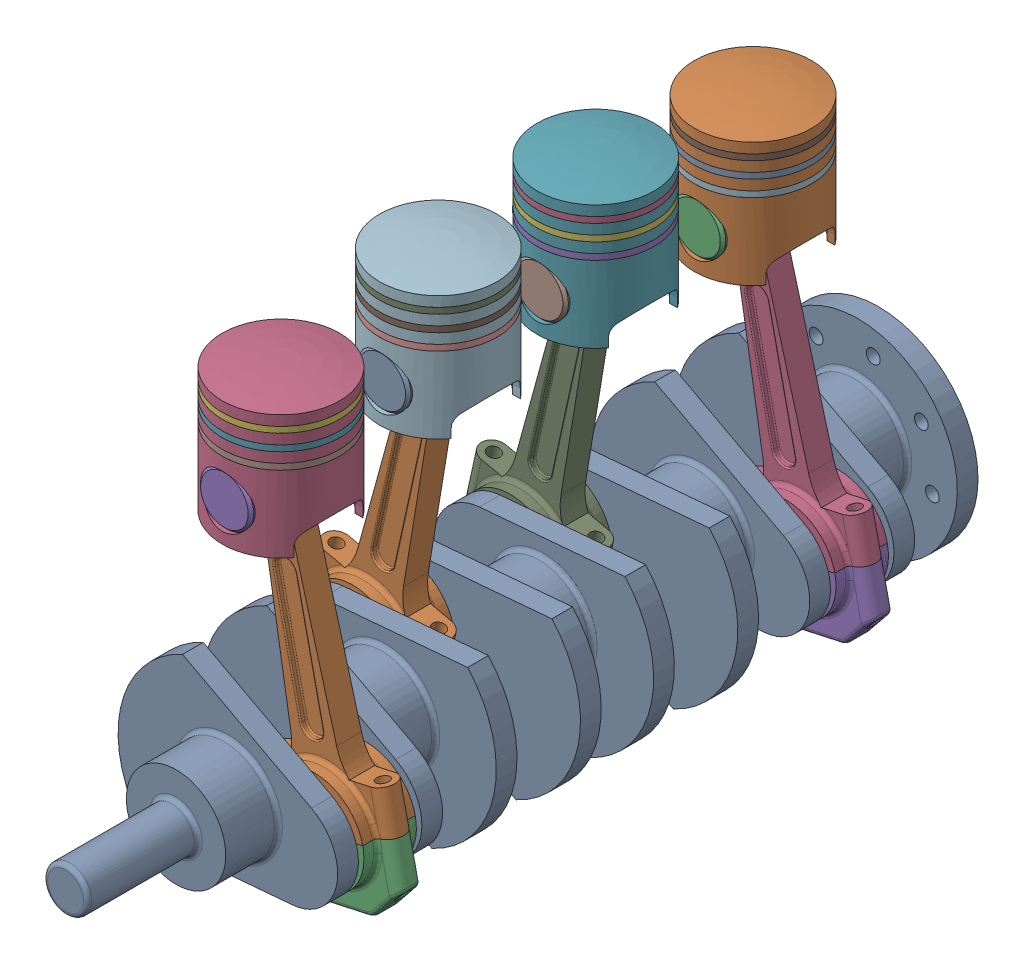
SolidWorks assembly Four cylinder engine, configuration Default. Lengths in mm.
Overall size (199.45 359.98 589).
29 component instances, 6 part files, 66 mates.
Components (placement in the parent):
- Crankshafts-1: Crankshafts [Default] at (0 0 456) x (0.200957 0.9796 0) z (0 0 1) size (144 160 589)
- Connecting rod-1: Connecting rod [Default] at (0 187.6868 433) x (0.976784 0.214227 0) z (0 0 1) size (94 223.7 38)
- Connecting Rod Cap-1: Connecting Rod Cap [Default] at (43.1024 -8.8421 433) x (0.976784 0.214227 0) z (0 0 -1) size (94 50 38)
- Piston-1: Piston [Default] at (0 160.6868 433) size (85 95 85)
- Piston Pin-1: Piston Pin [Default] at (0 187.6868 433) x (1 -0.000021 0) z (0 0 1) size (38.5 38.5 82)
- Piston Ring-1: Piston Ring [Default] at (0 239.0868 433) size (85 4.3 85)
- Piston Ring-2: Piston Ring [Default] at (0 227.4868 433) x (0.982082 0 -0.188455) z (0.188455 0 0.982082) size (85 4.3 85)
- Piston Ring-3: Piston Ring [Default] at (0 215.8868 433) x (0.918365 0 -0.395734) z (0.395734 0 0.918365) size (85 4.3 85)
- Piston Ring-4: Piston Ring [Default] at (0 256.771 319) x (0.941458 0 -0.337131) z (0.337131 0 0.941458) size (85 4.3 85)
- Piston Ring-5: Piston Ring [Default] at (0 233.571 319) x (0.731188 0 -0.682176) z (0.682176 0 0.731188) size (85 4.3 85)
- Piston Ring-6: Piston Ring [Default] at (0 245.171 319) x (0.861055 0 -0.508512) z (0.508512 0 0.861055) size (85 4.3 85)
- Piston-2: Piston [Default] at (0 178.371 319) size (85 95 85)
- Piston Pin-2: Piston Pin [Default] at (0 205.371 319) x (0.216805 -0.976215 0) z (0 0 1) size (38.5 38.5 82)
- Connecting rod-2: Connecting rod [Default] at (0 205.371 319) x (0.976784 -0.214227 0) z (0 0 1) size (94 223.7 38)
- Connecting Rod Cap-2: Connecting Rod Cap [Default] at (-43.1024 8.8421 319) x (0.976784 -0.214227 0) z (0 0 -1) size (94 50 38)
- Piston Ring-7: Piston Ring [Default] at (0 256.771 205) x (0.790546 0 -0.612403) z (0.612403 0 0.790546) size (85 4.3 85)
- Piston Ring-8: Piston Ring [Default] at (0 233.571 205) x (0.483661 0 -0.875255) z (0.875255 0 0.483661) size (85 4.3 85)
- Piston Ring-9: Piston Ring [Default] at (0 245.171 205) x (0.660971 0 -0.750412) z (0.750412 0 0.660971) size (85 4.3 85)
- Piston-3: Piston [Default] at (0 178.371 205) x (-1 0 0) z (0 0 -1) size (85 95 85)
- Piston Pin-3: Piston Pin [Default] at (0 205.371 205) x (-0.34204 0.939685 0) z (0 0 -1) size (38.5 38.5 82)
- Connecting rod-3: Connecting rod [Default] at (0 205.371 205) x (-0.976784 0.214227 0) z (0 0 -1) size (94 223.7 38)
- Connecting Rod Cap-3: Connecting Rod Cap [Default] at (-43.1024 8.8421 205) x (-0.976784 0.214227 0) z (0 0 1) size (94 50 38)
- Piston Ring-10: Piston Ring [Default] at (0 239.0868 91) x (0.849057 0 -0.528302) z (0.528302 0 0.849057) size (85 4.3 85)
- Piston Ring-11: Piston Ring [Default] at (0 215.8868 91) x (0.570677 0 -0.821175) z (0.821175 0 0.570677) size (85 4.3 85)
- Piston Ring-12: Piston Ring [Default] at (0 227.4868 91) x (0.734282 0 -0.678845) z (0.678845 0 0.734282) size (85 4.3 85)
- Piston-4: Piston [Default] at (0 160.6868 91) x (-1 0 0) z (0 0 -1) size (85 95 85)
- Piston Pin-4: Piston Pin [Default] at (0 187.6868 91) x (0.999917 0.012864 0) z (0 0 -1) size (38.5 38.5 82)
- Connecting rod-4: Connecting rod [Default] at (0 187.6868 91) x (-0.976784 -0.214227 0) z (0 0 -1) size (94 223.7 38)
- Connecting Rod Cap-4: Connecting Rod Cap [Default] at (43.1024 -8.8421 91) x (-0.976784 -0.214227 0) z (0 0 1) size (94 50 38)
Mates (geometry in assembly coordinates):
- Concentric1: concentric anti-aligned: cylinder of Crankshafts-1 through (0 0 167) axis (0 0 -1) radius 36
- Coincident2: coincident: plane of Crankshafts-1 through (0 0 589) normal (0 0 1)
- Coincident3: coincident aligned: plane of Piston-1 through (0 155.4734 433) normal (0 0 1); plane of Piston Pin-1 through (0 182.4734 433) normal (0 0 1)
- Concentric2: concentric anti-aligned: cylinder of Piston-1 through (0 182.4734 390.5) axis (0 0 1) radius 18.9; cylinder of Piston Pin-1 through (0 182.4734 474) axis (0 0 -1) radius 19.25
- Concentric3: concentric anti-aligned: cylinder of Piston-1 through (0 233.8734 433) axis (0 1 0) radius 39.5; cylinder of Piston Ring-1 through (0 238.1734 433) axis (0 -1 0) radius 39.5
- Coincident4: coincident anti-aligned: plane of Piston-1 through (0 233.8734 433) normal (0 1 0); plane of Piston Ring-1 through (0 233.8734 433) normal (0 -1 0)
- Concentric4: concentric anti-aligned: cylinder of Piston-1 through (0 222.2734 433) axis (0 1 0) radius 39.5; cylinder of Piston Ring-2 through (0 226.5734 433) axis (0 -1 0) radius 39.5
- Coincident5: coincident anti-aligned: plane of Piston-1 through (0 222.2734 433) normal (0 1 0); plane of Piston Ring-2 through (0 222.2734 433) normal (0 -1 0)
- Concentric5: concentric anti-aligned: cylinder of Piston-1 through (0 210.6734 433) axis (0 1 0) radius 39.5; cylinder of Piston Ring-3 through (0 214.9734 433) axis (0 -1 0) radius 39.5
- Coincident6: coincident anti-aligned: plane of Piston-1 through (0 210.6734 433) normal (0 1 0); plane of Piston Ring-3 through (0 210.6734 433) normal (0 -1 0)
- Coincident7: coincident aligned: plane of Connecting rod-1 through (0 182.4734 433) normal (0 0 1); plane of Piston Pin-1 through (0 182.4734 433) normal (0 0 1)
- Concentric6: concentric aligned: cylinder of Connecting rod-1 through (0 182.4734 452) axis (0 0 -1) radius 16.9; cylinder of Piston Pin-1 through (0 182.4734 474) axis (0 0 -1) radius 19.25
- Concentric7: concentric aligned: circle of Connecting rod-1; cylinder of Connecting Rod Cap-1 through (-89.0962 -55.4494 433) axis (0.206675 0.97841 0) radius 4.5
- Concentric8: concentric aligned: circle of Connecting rod-1; circle of Connecting Rod Cap-1
- Coincident10: coincident anti-aligned: plane of Connecting rod-1 through (-41.5829 -14.3826 452) normal (-0.206675 -0.97841 0); plane of Connecting Rod Cap-1 through (-76.8057 -6.9423 414) normal (0.206675 0.97841 0)
- Width1: width anti-aligned: plane of Crankshafts-1 through (0 0 410) normal (0 0 1); plane of Connecting rod-1 through (0 0 456) normal (0 0 -1); plane of Crankshafts-1 through (0 182.4734 424) normal (0 0 -1); plane of Connecting rod-1 through (0 182.4734 442) normal (0 0 1)
- Concentric9: concentric aligned: cylinder of Crankshafts-1 through (-41.5829 -14.3826 410) axis (0 0 1) radius 27; cylinder of Connecting Rod Cap-1 through (-41.5829 -14.3826 414) axis (0 0 1) radius 25.8515
- Concentric10: concentric anti-aligned: cylinder of Piston-1 through (0 245.4734 433) axis (0 -1 0) radius 42.5
- Coincident12: coincident aligned: plane of Piston-2 through (0 184.2386 319) normal (0 0 1); plane of Piston Pin-2 through (0 211.2386 319) normal (0 0 1)
- Concentric11: concentric anti-aligned: cylinder of Piston-2 through (0 211.2386 276.5) axis (0 0 1) radius 18.9; cylinder of Piston Pin-2 through (0 211.2386 360) axis (0 0 -1) radius 19.25
- Concentric12: concentric anti-aligned: cylinder of Piston Ring-4 through (0 266.9386 319) axis (0 -1 0) radius 39.5; cylinder of Piston-2 through (0 262.6386 319) axis (0 1 0) radius 39.5
- Coincident13: coincident anti-aligned: plane of Piston Ring-4 through (0 262.6386 319) normal (0 -1 0); plane of Piston-2 through (0 262.6386 319) normal (0 1 0)
- Concentric13: concentric anti-aligned: cylinder of Piston Ring-6 through (0 255.3386 319) axis (0 -1 0) radius 39.5; cylinder of Piston-2 through (0 251.0386 319) axis (0 1 0) radius 39.5
- Coincident14: coincident anti-aligned: plane of Piston Ring-6 through (0 251.0386 319) normal (0 -1 0); plane of Piston-2 through (0 251.0386 319) normal (0 1 0)
- Concentric14: concentric anti-aligned: cylinder of Piston Ring-5 through (0 243.7386 319) axis (0 -1 0) radius 39.5; cylinder of Piston-2 through (0 239.4386 319) axis (0 1 0) radius 39.5
- Coincident15: coincident anti-aligned: plane of Piston Ring-5 through (0 239.4386 319) normal (0 -1 0); plane of Piston-2 through (0 239.4386 319) normal (0 1 0)
- Coincident16: coincident aligned: plane of Piston Pin-2 through (0 211.2386 319) normal (0 0 1); plane of Connecting rod-2 through (0 211.2386 319) normal (0 0 1)
- Concentric15: concentric aligned: cylinder of Piston Pin-2 through (0 211.2386 360) axis (0 0 -1) radius 19.25; cylinder of Connecting rod-2 through (0 211.2386 338) axis (0 0 -1) radius 16.9
- Concentric16: concentric aligned: circle of Connecting rod-2; cylinder of Connecting Rod Cap-2 through (14.7371 -42.3915 319) axis (-0.206675 0.97841 0) radius 4.5
- Concentric17: concentric aligned: circle of Connecting rod-2; circle of Connecting Rod Cap-2
- Coincident17: coincident anti-aligned: plane of Connecting rod-2 through (41.5829 14.3826 338) normal (0.206675 -0.97841 0); plane of Connecting Rod Cap-2 through (6.3602 6.9423 300) normal (-0.206675 0.97841 0)
- Width2: width anti-aligned: plane of Crankshafts-1 through (0 0 342) normal (0 0 -1); plane of Connecting rod-2 through (0 0 296) normal (0 0 1); plane of Crankshafts-1 through (0 211.2386 310) normal (0 0 -1); plane of Connecting rod-2 through (0 211.2386 328) normal (0 0 1)
- Concentric18: concentric aligned: cylinder of Crankshafts-1 through (41.5829 14.3826 296) axis (0 0 1) radius 27; cylinder of Connecting Rod Cap-2 through (41.5829 14.3826 300) axis (0 0 1) radius 25.8515
- Concentric19: concentric anti-aligned: cylinder of Piston-2 through (0 274.2386 319) axis (0 -1 0) radius 42.5
- Coincident18: coincident aligned: plane of Piston-3 through (0 184.2386 205) normal (0 0 -1); plane of Piston Pin-3 through (0 211.2386 205) normal (0 0 -1)
- Concentric20: concentric anti-aligned: cylinder of Piston-3 through (0 211.2386 247.5) axis (0 0 -1) radius 18.9; cylinder of Piston Pin-3 through (0 211.2386 164) axis (0 0 1) radius 19.25
- Concentric21: concentric anti-aligned: cylinder of Piston Ring-7 through (0 266.9386 205) axis (0 -1 0) radius 39.5; cylinder of Piston-3 through (0 262.6386 205) axis (0 1 0) radius 39.5
- Coincident19: coincident anti-aligned: plane of Piston Ring-7 through (0 262.6386 205) normal (0 -1 0); plane of Piston-3 through (0 262.6386 205) normal (0 1 0)
- Concentric22: concentric anti-aligned: cylinder of Piston Ring-9 through (0 255.3386 205) axis (0 -1 0) radius 39.5; cylinder of Piston-3 through (0 251.0386 205) axis (0 1 0) radius 39.5
- Coincident20: coincident anti-aligned: plane of Piston Ring-9 through (0 251.0386 205) normal (0 -1 0); plane of Piston-3 through (0 251.0386 205) normal (0 1 0)
- Concentric23: concentric anti-aligned: cylinder of Piston Ring-8 through (0 243.7386 205) axis (0 -1 0) radius 39.5; cylinder of Piston-3 through (0 239.4386 205) axis (0 1 0) radius 39.5
- Coincident21: coincident anti-aligned: plane of Piston Ring-8 through (0 239.4386 205) normal (0 -1 0); plane of Piston-3 through (0 239.4386 205) normal (0 1 0)
- Coincident22: coincident aligned: plane of Piston Pin-3 through (0 211.2386 205) normal (0 0 -1); plane of Connecting rod-3 through (0 211.2386 205) normal (0 0 -1)
- Concentric24: concentric aligned: cylinder of Piston Pin-3 through (0 211.2386 164) axis (0 0 1) radius 19.25; cylinder of Connecting rod-3 through (0 211.2386 186) axis (0 0 1) radius 16.9
- Concentric25: concentric aligned: circle of Connecting rod-3; cylinder of Connecting Rod Cap-3 through (89.0962 -26.6843 205) axis (-0.206675 0.97841 0) radius 4.5
- Concentric26: concentric aligned: circle of Connecting rod-3; circle of Connecting Rod Cap-3
- Coincident23: coincident anti-aligned: unknown of Connecting rod-3; unknown of Connecting Rod Cap-3
- Width3: width anti-aligned: plane of Crankshafts-1 through (0 0 228) normal (0 0 -1); plane of Connecting rod-3 through (0 0 182) normal (0 0 1); plane of Crankshafts-1 through (0 211.2386 214) normal (0 0 1); plane of Connecting rod-3 through (0 211.2386 196) normal (0 0 -1)
- Concentric27: concentric aligned: cylinder of Crankshafts-1 through (41.5829 14.3826 228) axis (0 0 -1) radius 27; cylinder of Connecting Rod Cap-3 through (41.5829 14.3826 224) axis (0 0 -1) radius 25.8515
- Concentric28: concentric anti-aligned: cylinder of Piston-3 through (0 274.2386 205) axis (0 -1 0) radius 42.5
- Coincident24: coincident aligned: plane of Piston-4 through (0 155.4734 91) normal (0 0 -1); plane of Piston Pin-4 through (0 182.4734 91) normal (0 0 -1)
- Concentric29: concentric anti-aligned: cylinder of Piston-4 through (0 182.4734 133.5) axis (0 0 -1) radius 18.9; cylinder of Piston Pin-4 through (0 182.4734 50) axis (0 0 1) radius 19.25
- Concentric30: concentric anti-aligned: cylinder of Piston Ring-10 through (0 238.1734 91) axis (0 -1 0) radius 39.5; cylinder of Piston-4 through (0 233.8734 91) axis (0 1 0) radius 39.5
- Coincident25: coincident anti-aligned: plane of Piston Ring-10 through (0 233.8734 91) normal (0 -1 0); plane of Piston-4 through (0 233.8734 91) normal (0 1 0)
- Concentric31: concentric anti-aligned: cylinder of Piston Ring-12 through (0 226.5734 91) axis (0 -1 0) radius 39.5; cylinder of Piston-4 through (0 222.2734 91) axis (0 1 0) radius 39.5
- Coincident26: coincident anti-aligned: plane of Piston Ring-12 through (0 222.2734 91) normal (0 -1 0); plane of Piston-4 through (0 222.2734 91) normal (0 1 0)
- Concentric32: concentric anti-aligned: cylinder of Piston Ring-11 through (0 214.9734 91) axis (0 -1 0) radius 39.5; cylinder of Piston-4 through (0 210.6734 91) axis (0 1 0) radius 39.5
- Coincident27: coincident anti-aligned: plane of Piston Ring-11 through (0 210.6734 91) normal (0 -1 0); plane of Piston-4 through (0 210.6734 91) normal (0 1 0)
- Coincident28: coincident aligned: plane of Piston Pin-4 through (0 182.4734 91) normal (0 0 -1); plane of Connecting rod-4 through (0 182.4734 91) normal (0 0 -1)
- Concentric33: concentric aligned: cylinder of Piston Pin-4 through (0 182.4734 50) axis (0 0 1) radius 19.25; cylinder of Connecting rod-4 through (0 182.4734 72) axis (0 0 1) radius 16.9
- Concentric34: concentric aligned: circle of Connecting rod-4; cylinder of Connecting Rod Cap-4 through (-14.7371 -71.1567 91) axis (0.206675 0.97841 0) radius 4.5
- Concentric35: concentric aligned: circle of Connecting rod-4; circle of Connecting Rod Cap-4
- Coincident29: coincident anti-aligned: plane of Connecting rod-4 through (-41.5829 -14.3826 72) normal (-0.206675 -0.97841 0); plane of Connecting Rod Cap-4 through (-6.3602 -21.8229 110) normal (0.206675 0.97841 0)
- Width4: width anti-aligned: plane of Crankshafts-1 through (0 0 68) normal (0 0 1); plane of Connecting rod-4 through (0 0 114) normal (0 0 -1); plane of Crankshafts-1 through (0 182.4734 100) normal (0 0 1); plane of Connecting rod-4 through (0 182.4734 82) normal (0 0 -1)
- Concentric36: concentric aligned: cylinder of Crankshafts-1 through (-41.5829 -14.3826 114) axis (0 0 -1) radius 27; cylinder of Connecting Rod Cap-4 through (-41.5829 -14.3826 110) axis (0 0 -1) radius 25.8515
- Concentric37: concentric anti-aligned: cylinder of Piston-4 through (0 245.4734 91) axis (0 -1 0) radius 42.5
